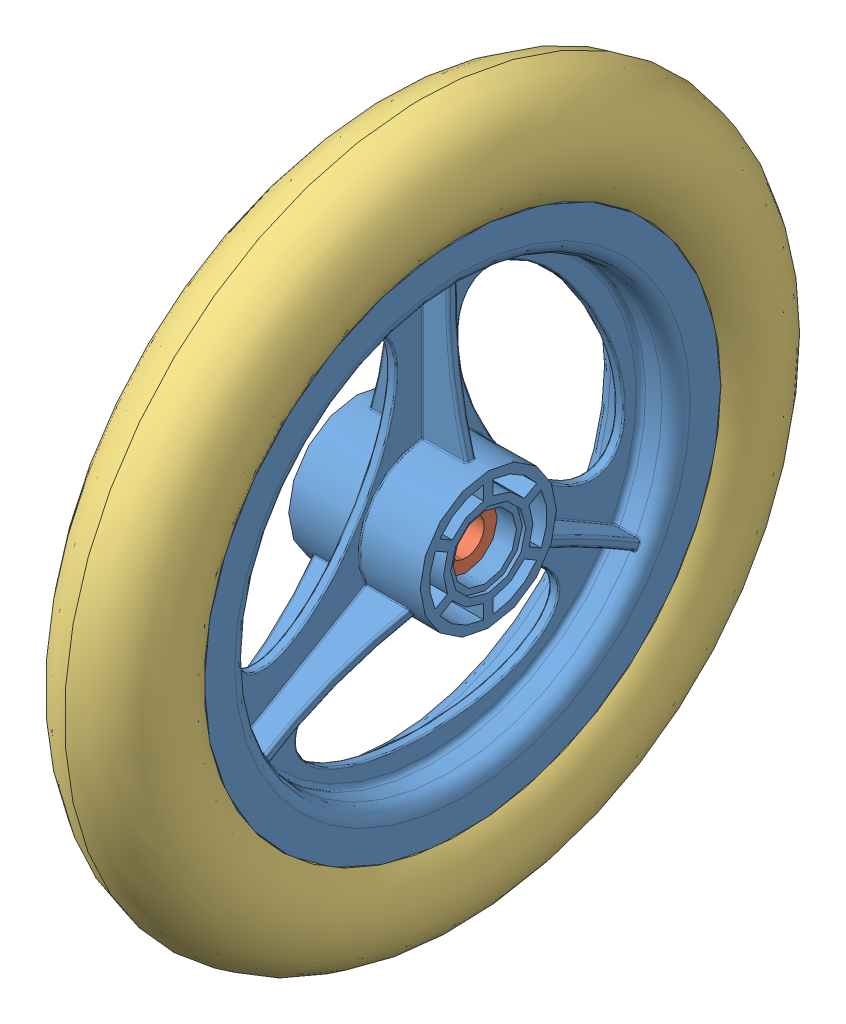
SolidWorks assembly 12 Inch Wheel, configuration Default. Lengths in mm.
Overall size (56 304.8 304.8).
3 component instances, 3 part files, 0 mates.
Components (placement in the parent):
- 12 Inch Wheel Outer Hub-1: 12 Inch Wheel Outer Hub [Default] at origin size (56 220 220)
- 12 Inch Wheel Inner Hub-1: 12 Inch Wheel Inner Hub [Default] at (18.355 0 0) x (0 0 1) z (-1 0 0) size (27 27 46.36)
- 12 Inch Tire-1: 12 Inch Tire [Default] at origin size (46.35 304.8 304.8)
